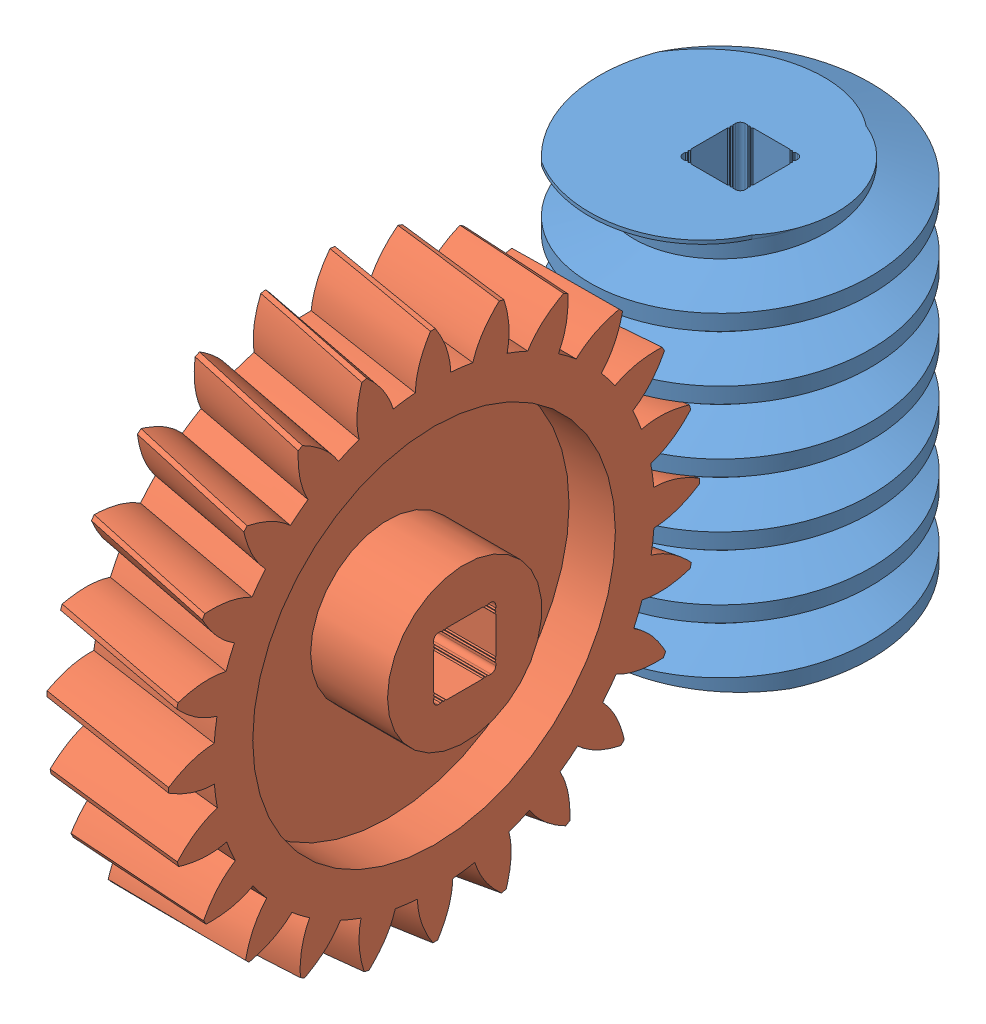
SolidWorks assembly WORM-ASSY, configuration Default. Lengths in mm.
Overall size (15.42 27.52 40.56).
2 component instances, 2 part files, 0 mates.
Components (placement in the parent):
- WORM-1: WORM [Default] at origin size (15.42 20.65 15.51)
- Worm-Wheel-1: Worm-Wheel [Default] at (0 8.5 19.05) x (0 -1 0) z (0 0 1) size (27.52 9.53 27.52)
